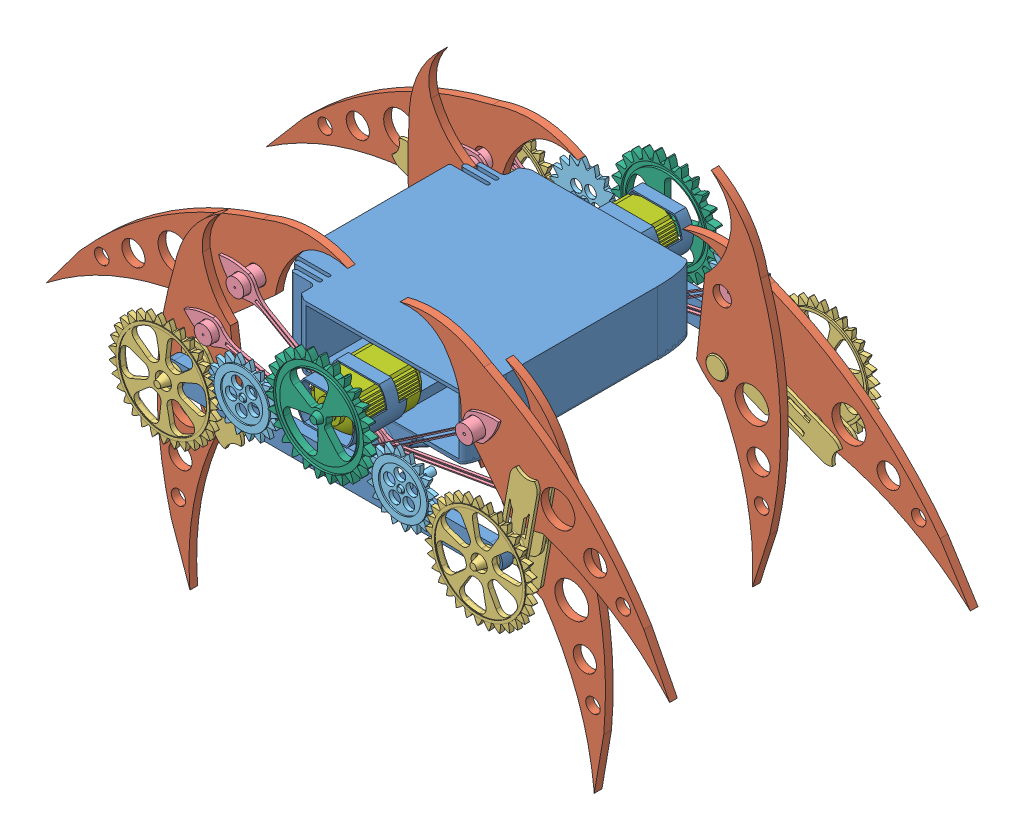
SolidWorks assembly Spider F-Robot, configuration Défaut. Lengths in mm.
Overall size (48.09 26.53 23.55).
29 component instances, 7 part files, 73 mates.
Components (placement in the parent):
- chassit(1)-1: chassit(1) [Défaut] at (-38.9442 2.2697 9.8426) size (22.09 6 21.97)
- patte(2)-1: patte(2) [Défaut] at (-28.4392 -1.2519 8.3426) x (0.681301 0.732004 0) z (0 0 1) size (5.42 22.16 0.5)
- vilbreQ(3)-1: vilbreQ(3) [Défaut] at (-28.1694 6.0381 8.8426) x (0.17907 0.983836 0) z (0 0 1) size (7.89 7.06 5.2)
- bielle(4)-1: bielle(4) [Défaut] at (-39.4261 2.5576 9.1426) x (0.824364 0.56606 0) z (0 0 -1) size (12.71 1.65 1.43)
- patte(2)-2: patte(2) [Défaut] at (-33.2678 -4.6344 6.6426) x (0.984138 0.177405 0) z (0 0 1) size (5.42 22.16 0.5)
- bielle(4)-2: bielle(4) [Défaut] at (-39.5997 2.8057 7.6926) x (0.985206 0.171372 0) z (0 0 -1) size (12.71 1.65 1.43)
- vilbreQ(3)-2: vilbreQ(3) [Défaut] at (-25.9212 1.9491 -8.8426) x (0.926662 -0.375896 0) z (0 0 -1) size (7.89 7.06 5.2)
- patte(2)-3: patte(2) [Défaut] at (-26.0736 -4.439 -8.8426) x (0.611843 0.79098 0) z (0 0 1) size (5.42 22.16 0.5)
- patte(2)-4: patte(2) [Défaut] at (-35.8472 -0.5737 -7.0426) x (0.999277 0.03803 0) z (0 0 1) size (5.42 22.16 0.5)
- bielle(4)-3: bielle(4) [Défaut] at (-39.6158 2.8481 -7.5726) x (0.849746 0.527193 0) z (0 0 1) size (12.71 1.65 1.43)
- bielle(4)-4: bielle(4) [Défaut] at (-39.6545 3.0898 -9.2226) x (0.978244 0.207458 0) z (0 0 1) size (12.71 1.65 1.43)
- vilbreQ(3)-3: vilbreQ(3) [Défaut] at (-51.9756 4.1888 -8.8426) x (-0.92947 0.368897 0) z (0 0 -1) size (7.89 7.06 5.2)
- patte(2)-5: patte(2) [Défaut] at (-41.0784 -1.1841 -6.5426) x (-0.979725 -0.200349 0) z (0 0 -1) size (5.42 22.16 0.5)
- patte(2)-6: patte(2) [Défaut] at (-52.7584 -2.5543 -8.3426) x (-0.493364 0.869823 0) z (0 0 -1) size (5.42 22.16 0.5)
- bielle(4)-5: bielle(4) [Défaut] at (-38.3472 2.6944 -9.4806) x (-0.939588 0.342307 0) z (0 0 1) size (12.71 1.65 1.43)
- bielle(4)-6: bielle(4) [Défaut] at (-38.3353 2.7135 -7.9806) x (-0.94993 0.312463 0) z (0 0 1) size (12.71 1.65 1.43)
- vilbreQ(3)-4: vilbreQ(3) [Défaut] at (-47.5812 0.5328 8.8426) x (0.531823 -0.846856 0) z (0 0 1) size (7.89 7.06 5.2)
- patte(2)-7: patte(2) [Défaut] at (-42.9964 -3.373 8.8426) x (-0.999964 0.008501 0) z (0 0 -1) size (5.42 22.16 0.5)
- patte(2)-8: patte(2) [Défaut] at (-51.5018 -1.358 7.0426) x (-0.54715 0.837035 0) z (0 0 -1) size (5.42 22.16 0.5)
- bielle(4)-7: bielle(4) [Défaut] at (-38.3034 2.7728 8.8576) x (-0.975262 0.22105 0) z (0 0 1) size (12.71 1.65 1.43)
- bielle(4)-8: bielle(4) [Défaut] at (-38.4205 2.5995 7.8226) x (-0.868639 0.495446 0) z (0 0 1) size (12.71 1.65 1.43)
- pignon (inter)-3: pignon (inter) [Défaut] at (-44.0624 4.6678 10.9426) x (-0.175775 0.98443 0) z (0 0 1) size (4.57 4.5 2.16)
- pignon (inter)-4: pignon (inter) [Défaut] at (-33.826 4.6678 10.9426) x (0.227468 0.973786 0) z (0 0 1) size (4.57 4.5 2.16)
- pignon (inter)-5: pignon (inter) [Défaut] at (-33.826 4.6678 -10.9426) x (-0.836881 0.547386 0) z (0 0 -1) size (4.57 4.5 2.16)
- pignon (inter)-6: pignon (inter) [Défaut] at (-44.0624 4.6678 -10.9426) x (0.419439 -0.907783 0) z (0 0 -1) size (4.57 4.5 2.16)
- pignon moteur-1: pignon moteur [Défaut] at (-38.9379 6.2597 10.9926) x (-0.942546 -0.334076 0) z (0 0 1) size (6.92 6.88 3.68)
- pignon moteur-2: pignon moteur [Défaut] at (-38.9379 6.2597 -10.9926) x (0.784328 -0.620346 0) z (0 0 -1) size (6.92 6.88 3.68)
- moteur(5)-3: moteur(5) [Défaut] at (-38.9379 6.2597 6.6146) size (3.6 3.17 4.7)
- moteur(5)-4: moteur(5) [Défaut] at (-38.9379 6.2597 -6.6146) x (-1 0 0) z (0 0 -1) size (3.6 3.17 4.7)
Mates (geometry in assembly coordinates):
- Coaxiale7: concentric anti-aligned: cylinder of chassit(1)-1 through (-38.9442 3.0795 10.7426) axis (0 0 -1) radius 0.5; cylinder of bielle(4)-1 through (-38.9442 3.0795 8.9626) axis (0 0 1) radius 0.6
- Coaxiale8: concentric aligned: cylinder of patte(2)-1 through (-29.5351 5.2154 8.8426) axis (0 0 -1) radius 0.6; cylinder of bielle(4)-1 through (-29.5351 5.2154 9.1576) axis (0 0 -1) radius 0.5713
- Coaxiale9: concentric aligned: cylinder of chassit(1)-1 through (-28.7079 3.0795 10.5426) axis (0 0 -1) radius 0.6; cylinder of vilbreQ(3)-1 through (-28.7079 3.0795 10.7426) axis (0 0 -1) radius 0.6
- Coïncidente7: coincident anti-aligned: plane of chassit(1)-1 through (-28.7079 3.0795 10.5426) normal (0 0 1); plane of vilbreQ(3)-1 through (-28.7079 3.0795 10.5426) normal (0 0 -1)
- Coaxiale10: concentric anti-aligned: cylinder of patte(2)-1 through (-29.9655 1.0896 8.8426) axis (0 0 -1) radius 0.6; cylinder of vilbreQ(3)-1 through (-29.9655 1.0896 7.9426) axis (0 0 1) radius 0.6
- Coïncidente8: coincident anti-aligned: plane of patte(2)-1 through (-30.668 0.1114 8.8426) normal (0 0 1); plane of vilbreQ(3)-1 through (-33.4855 4.1956 8.8426) normal (0 0 -1)
- Coaxiale11: concentric anti-aligned: cylinder of vilbreQ(3)-1 through (-27.3583 5.2149 6.5426) axis (0 0 1) radius 0.6; cylinder of patte(2)-2 through (-27.3583 5.2149 7.1426) axis (0 0 -1) radius 0.6
- Coïncidente9: coincident anti-aligned: plane of vilbreQ(3)-1 through (-26.0815 7.235 7.1426) normal (0 0 -1); plane of patte(2)-2 through (-26.931 4.0889 7.1426) normal (0 0 1)
- Coaxiale12: concentric aligned: cylinder of patte(2)-2 through (-30.5593 7.8531 7.1426) axis (0 0 -1) radius 0.6; cylinder of bielle(4)-2 through (-30.5593 7.8531 7.7076) axis (0 0 -1) radius 0.5713
- Distance1: distance = 0.37 mm anti-aligned: plane of patte(2)-2 through (-29.6859 -0.4894 7.1426) normal (0 0 1); plane of bielle(4)-2 through (-35.6915 13.9098 7.5126) normal (0 0 -1)
- Coaxiale13: concentric anti-aligned: cylinder of chassit(1)-1 through (-38.9442 3.0795 10.7426) axis (0 0 -1) radius 0.5; cylinder of bielle(4)-2 through (-38.9442 3.0795 7.5126) axis (0 0 1) radius 0.6
- Coaxiale14: concentric aligned: cylinder of chassit(1)-1 through (-28.7079 3.0795 -10.5426) axis (0 0 1) radius 0.6; cylinder of vilbreQ(3)-2 through (-28.7079 3.0795 -10.7426) axis (0 0 1) radius 0.6
- Coïncidente11: coincident anti-aligned: plane of chassit(1)-1 through (-28.7079 3.0795 -10.5426) normal (0 0 -1); plane of vilbreQ(3)-2 through (-28.7079 3.0795 -10.5426) normal (0 0 1)
- Coaxiale15: concentric aligned: cylinder of vilbreQ(3)-2 through (-30.8965 4.3409 -6.5426) axis (0 0 -1) radius 0.6; cylinder of patte(2)-4 through (-30.8965 4.3409 -6.5426) axis (0 0 -1) radius 0.6
- Coïncidente12: coincident anti-aligned: plane of vilbreQ(3)-2 through (-30.8965 4.3409 -6.5426) normal (0 0 -1); plane of patte(2)-4 through (-31.479 3.2868 -6.5426) normal (0 0 1)
- Coaxiale16: concentric aligned: cylinder of vilbreQ(3)-2 through (-26.6684 1.904 -7.9426) axis (0 0 -1) radius 0.6; cylinder of patte(2)-3 through (-26.6684 1.904 -8.3426) axis (0 0 -1) radius 0.6
- Coïncidente13: coincident anti-aligned: plane of vilbreQ(3)-2 through (-24.9994 6.2917 -8.8426) normal (0 0 1); plane of patte(2)-3 through (-26.3987 0.7303 -8.8426) normal (0 0 -1)
- Coaxiale17: concentric anti-aligned: cylinder of patte(2)-4 through (-30.9546 8.4886 -6.5426) axis (0 0 -1) radius 0.6; cylinder of bielle(4)-3 through (-30.9546 8.4886 -7.5876) axis (0 0 1) radius 0.5713
- Distance2: distance = 0.35 mm anti-aligned: plane of bielle(4)-3 through (-29.3127 -2.8458 -7.3926) normal (0 0 1); plane of patte(2)-4 through (-31.7208 3.0297 -7.0426) normal (0 0 -1)
- Coaxiale18: concentric anti-aligned: cylinder of chassit(1)-1 through (-38.9442 3.0795 -10.7426) axis (0 0 1) radius 0.5; cylinder of bielle(4)-3 through (-38.9442 3.0795 -7.3926) axis (0 0 -1) radius 0.6
- Coaxiale19: concentric anti-aligned: cylinder of patte(2)-3 through (-29.4796 4.9543 -8.3426) axis (0 0 -1) radius 0.6; cylinder of bielle(4)-4 through (-29.4796 4.9543 -9.2376) axis (0 0 1) radius 0.5713
- Coaxiale20: concentric anti-aligned: cylinder of chassit(1)-1 through (-38.9442 3.0795 -10.7426) axis (0 0 1) radius 0.5; cylinder of bielle(4)-4 through (-38.9442 3.0795 -9.0426) axis (0 0 -1) radius 0.6
- Coaxiale21: concentric aligned: cylinder of chassit(1)-1 through (-49.1805 3.0795 -10.5426) axis (0 0 1) radius 0.6; cylinder of vilbreQ(3)-3 through (-49.1805 3.0795 -10.7426) axis (0 0 1) radius 0.6
- Coïncidente16: coincident anti-aligned: plane of chassit(1)-1 through (-28.7079 3.0795 -10.5426) normal (0 0 -1); plane of vilbreQ(3)-3 through (-49.1805 3.0795 -10.5426) normal (0 0 1)
- Coaxiale22: concentric anti-aligned: cylinder of vilbreQ(3)-3 through (-51.2288 4.2395 -7.9426) axis (0 0 -1) radius 0.6; cylinder of patte(2)-6 through (-51.2288 4.2395 -8.8426) axis (0 0 1) radius 0.6
- Coïncidente17: coincident anti-aligned: plane of vilbreQ(3)-3 through (-52.8647 -0.1606 -8.8426) normal (0 0 1); plane of patte(2)-6 through (-51.7171 3.1386 -8.8426) normal (0 0 -1)
- Coaxiale23: concentric anti-aligned: cylinder of vilbreQ(3)-3 through (-46.9824 1.8346 -6.5426) axis (0 0 -1) radius 0.6; cylinder of patte(2)-5 through (-46.9824 1.8346 -7.0426) axis (0 0 1) radius 0.6
- Coïncidente18: coincident anti-aligned: plane of vilbreQ(3)-3 through (-46.9824 1.8346 -6.5426) normal (0 0 -1); plane of patte(2)-5 through (-46.1043 1.0104 -6.5426) normal (0 0 1)
- Coaxiale24: concentric aligned: cylinder of patte(2)-6 through (-47.8882 6.6986 -8.8426) axis (0 0 1) radius 0.6; cylinder of bielle(4)-5 through (-47.8882 6.6986 -9.4956) axis (0 0 1) radius 0.5713
- Coaxiale25: concentric anti-aligned: cylinder of chassit(1)-1 through (-38.9442 3.0795 -10.7426) axis (0 0 1) radius 0.5; cylinder of bielle(4)-5 through (-38.9442 3.0795 -9.3006) axis (0 0 -1) radius 0.6
- Coïncidente19: coincident anti-aligned: plane of patte(2)-6 through (-51.7171 3.1386 -8.8426) normal (0 0 -1); plane of bielle(4)-5 through (-47.8882 6.6986 -8.8426) normal (0 0 1)
- Coaxiale26: concentric anti-aligned: cylinder of chassit(1)-1 through (-38.9442 3.0795 -10.7426) axis (0 0 1) radius 0.5; cylinder of bielle(4)-6 through (-38.9442 3.0795 -7.8006) axis (0 0 -1) radius 0.6
- Coaxiale27: concentric aligned: cylinder of patte(2)-5 through (-48.2013 5.7996 -7.0426) axis (0 0 1) radius 0.6; cylinder of bielle(4)-6 through (-48.2013 5.7996 -7.9956) axis (0 0 1) radius 0.5713
- Distance3: distance = 0.3 mm anti-aligned: plane of bielle(4)-6 through (-48.1096 6.0943 -7.3426) normal (0 0 1); plane of patte(2)-5 through (-45.9424 1.3364 -7.0426) normal (0 0 -1)
- Coaxiale28: concentric aligned: cylinder of chassit(1)-1 through (-49.1805 3.0795 10.5426) axis (0 0 -1) radius 0.6; cylinder of vilbreQ(3)-4 through (-49.1805 3.0795 10.7426) axis (0 0 -1) radius 0.6
- Coïncidente21: coincident anti-aligned: plane of chassit(1)-1 through (-28.7079 3.0795 10.5426) normal (0 0 1); plane of vilbreQ(3)-4 through (-49.1805 3.0795 10.5426) normal (0 0 -1)
- Coaxiale29: concentric aligned: cylinder of vilbreQ(3)-4 through (-51.4267 3.7835 7.9426) axis (0 0 1) radius 0.6; cylinder of patte(2)-7 through (-51.4267 3.7835 8.3426) axis (0 0 1) radius 0.6
- Coïncidente22: coincident anti-aligned: plane of vilbreQ(3)-4 through (-49.3296 7.9835 8.8426) normal (0 0 -1); plane of patte(2)-7 through (-51.9231 2.6863 8.8426) normal (0 0 1)
- Coaxiale30: concentric aligned: cylinder of vilbreQ(3)-4 through (-46.77 2.3239 6.5426) axis (0 0 1) radius 0.6; cylinder of patte(2)-8 through (-46.77 2.3239 6.5426) axis (0 0 1) radius 0.6
- Coïncidente23: coincident anti-aligned: plane of vilbreQ(3)-4 through (-46.77 2.3239 6.5426) normal (0 0 1); plane of patte(2)-8 through (-45.8792 1.5134 6.5426) normal (0 0 -1)
- Coaxiale31: concentric aligned: cylinder of chassit(1)-1 through (-38.9442 3.0795 10.7426) axis (0 0 -1) radius 0.5; cylinder of bielle(4)-8 through (-38.9442 3.0795 8.0026) axis (0 0 -1) radius 0.6
- Coaxiale32: concentric aligned: cylinder of chassit(1)-1 through (-38.9442 3.0795 10.7426) axis (0 0 -1) radius 0.5; cylinder of bielle(4)-7 through (-38.9442 3.0795 9.0376) axis (0 0 -1) radius 0.6
- Coaxiale34: concentric aligned: cylinder of patte(2)-8 through (-48.05 6.2697 6.5426) axis (0 0 1) radius 0.6; cylinder of bielle(4)-8 through (-48.05 6.2697 7.8076) axis (0 0 1) radius 0.5713
- Distance4: distance = 0.78 mm anti-aligned: plane of patte(2)-8 through (-50.9503 4.0924 7.0426) normal (0 0 1); plane of bielle(4)-8 through (-38.3298 14.371 7.8226) normal (0 0 -1)
- Coïncidente25: coincident anti-aligned: plane of patte(2)-7 through (-51.9231 2.6863 8.8426) normal (0 0 1); plane of bielle(4)-7 through (-48.068 6.2178 8.8426) normal (0 0 -1)
- Coaxiale35: concentric aligned: cylinder of patte(2)-7 through (-48.068 6.2178 8.3426) axis (0 0 1) radius 0.6; cylinder of bielle(4)-7 through (-48.068 6.2178 8.8426) axis (0 0 1) radius 0.5713
- Coaxiale38: concentric aligned: cylinder of chassit(1)-1 through (-44.0624 4.6678 10.0226) axis (0 0 1) radius 0.2474; cylinder of pignon (inter)-3 through (-44.0624 4.6678 9.1426) axis (0 0 1) radius 0.2476
- Coïncidente28: coincident aligned: plane of vilbreQ(3)-4 through (-49.1805 3.0795 11.2926) normal (0 0 1); plane of pignon (inter)-3 through (-44.0624 4.6678 11.2926) normal (0 0 1)
- Coaxiale39: concentric aligned: cylinder of chassit(1)-1 through (-33.826 4.6678 10.0226) axis (0 0 1) radius 0.2474; cylinder of pignon (inter)-4 through (-33.826 4.6678 9.1426) axis (0 0 1) radius 0.2476
- Coïncidente29: coincident aligned: plane of vilbreQ(3)-1 through (-28.7079 3.0795 11.2926) normal (0 0 1); plane of pignon (inter)-4 through (-33.826 4.6678 11.2926) normal (0 0 1)
- Coaxiale40: concentric aligned: cylinder of chassit(1)-1 through (-33.826 4.6678 -10.0226) axis (0 0 -1) radius 0.2474; cylinder of pignon (inter)-5 through (-33.826 4.6678 -9.1426) axis (0 0 -1) radius 0.2476
- Coïncidente30: coincident aligned: plane of vilbreQ(3)-2 through (-28.7079 3.0795 -11.2926) normal (0 0 -1); plane of pignon (inter)-5 through (-33.826 4.6678 -11.2926) normal (0 0 -1)
- Coaxiale41: concentric aligned: cylinder of chassit(1)-1 through (-44.0624 4.6678 -10.0226) axis (0 0 -1) radius 0.2474; cylinder of pignon (inter)-6 through (-44.0624 4.6678 -9.1426) axis (0 0 -1) radius 0.2476
- Coïncidente31: coincident aligned: plane of vilbreQ(3)-3 through (-49.1805 3.0795 -11.2926) normal (0 0 -1); plane of pignon (inter)-6 through (-44.0624 4.6678 -11.2926) normal (0 0 -1)
- Coïncidente33: coincident anti-aligned: plane of chassit(1)-1 through (-38.9442 5.0862 7.5874) normal (0 1 0); plane of moteur(5)-3 through (-38.9379 5.0862 10.1146) normal (0 -1 0)
- Coïncidente37: coincident: cylinder of chassit(1)-1 through (-38.9442 6.2562 7.5874) axis (0 0 1) radius 1.8; line of moteur(5)-3 through (-40.4182 7.2893 10.1146) axis (0 0 -1)
- Coïncidente38: coincident aligned: plane of moteur(5)-3 through (-38.9379 6.2597 6.1146) normal (0 0 -1); plane of chassit(1)-1 through (-39.4442 7.6881 6.1146) normal (0 0 -1)
- Coaxiale44: concentric aligned: cylinder of pignon moteur-1 through (-38.9379 6.2597 8.0926) axis (0 0 1) radius 0.2464; cylinder of moteur(5)-3 through (-38.9379 6.2597 10.1146) axis (0 0 1) radius 0.7522
- Coïncidente40: coincident aligned: plane of pignon (inter)-3 through (-44.0624 4.6678 11.2926) normal (0 0 1); plane of pignon moteur-1 through (-38.9379 6.2597 11.2926) normal (0 0 1)
- Coïncidente41: coincident anti-aligned: plane of chassit(1)-1 through (-38.9442 5.0862 -7.5874) normal (0 1 0); plane of moteur(5)-4 through (-38.9379 5.0862 -10.1146) normal (0 -1 0)
- Coïncidente42: coincident aligned: plane of chassit(1)-1 through (-39.4442 7.6881 -6.1146) normal (0 0 1); plane of moteur(5)-4 through (-38.9379 6.2597 -6.1146) normal (0 0 1)
- Coïncidente43: coincident: cylinder of chassit(1)-1 through (-38.9442 6.2562 -7.5874) axis (0 0 -1) radius 1.8; line of moteur(5)-4 through (-40.4182 7.2893 -10.1146) axis (0 0 1)
- Coaxiale45: concentric aligned: cylinder of pignon moteur-2 through (-38.9379 6.2597 -8.0926) axis (0 0 -1) radius 0.2464; cylinder of moteur(5)-4 through (-38.9379 6.2597 -10.1146) axis (0 0 -1) radius 0.2445
- Coïncidente44: coincident aligned: plane of pignon (inter)-6 through (-44.0624 4.6678 -11.2926) normal (0 0 -1); plane of pignon moteur-2 through (-38.9379 6.2597 -11.2926) normal (0 0 -1)
- Contr.Engrenages1: gear = 3.567 : 5.8304 mm: circle of pignon moteur-2; circle of pignon (inter)-5
- Contr.Engrenages2: gear = 6.0724 : 3.567 mm: circle of pignon (inter)-5; circle of vilbreQ(3)-2
- Contr.Engrenages3: gear = 3.567 : 5.8304 mm: circle of pignon moteur-2; circle of pignon (inter)-6
- Contr.Engrenages4: gear = 6.0724 : 3.567 mm: circle of pignon (inter)-6; circle of vilbreQ(3)-3
- Contr.Engrenages5: gear = 3.567 : 5.8304 mm: circle of pignon moteur-1; circle of pignon (inter)-4
- Contr.Engrenages6: gear = 3.567 : 6.0724 mm: circle of vilbreQ(3)-1; circle of pignon (inter)-4
- Contr.Engrenages7: gear = 3.567 : 5.8304 mm: circle of pignon moteur-1; circle of pignon (inter)-3
- Contr.Engrenages8: gear = 6.0724 : 3.567 mm: circle of pignon (inter)-3; circle of vilbreQ(3)-4
- Coincident1: coincident anti-aligned: plane of vilbreQ(3)-2 through (-26.6684 1.904 -9.0426) normal (0 0 -1); plane of bielle(4)-4 through (-32.0151 -5.8571 -9.0426) normal (0 0 1)
